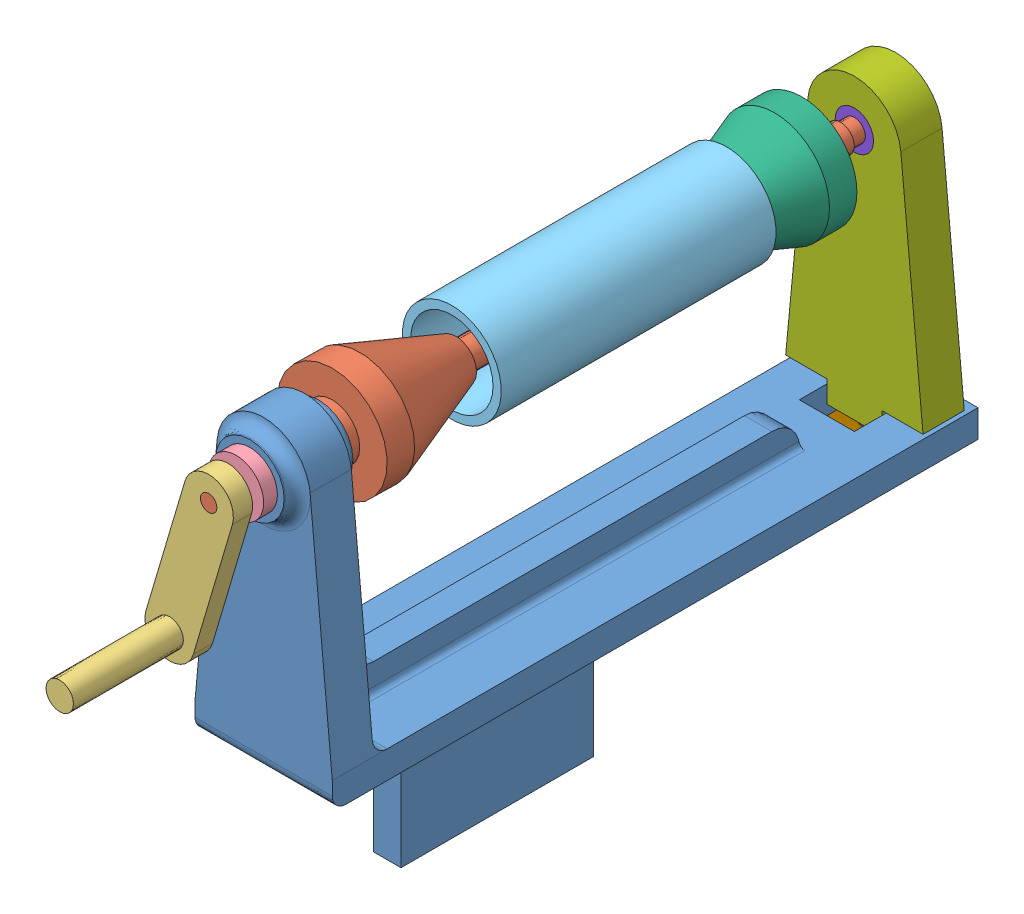
SolidWorks assembly Assem1, configuration Default. Lengths in mm.
Overall size (54.57 172.28 302.5).
10 component instances, 10 part files, 17 mates.
Components (placement in the parent):
- Ak Body-1: Ak Body [Default] at (61.2452 109.5735 296.2615) size (50 162 240)
- Ak Spindle-1: Ak Spindle [Default] at (61.2452 204.5735 73.7615) x (0 0 1) z (-0.495545 0.868582 0) size (250 40 40)
- Ak Spindle Handle-1: Ak Spindle Handle [Default] at (54.147 180.6024 323.7615) x (-0.958846 0.283926 0) z (0 0 -1) size (18 68 47)
- Ak Spindle Locking Nut-1: Ak Spindle Locking Nut [Default] at (61.2452 204.5735 308.7615) x (0.507715 0.861525 0) z (0 0 1) size (20 20 5)
- Ak Coil Former-1: Ak Coil Former [Default] at (61.2452 204.5735 235.2599) x (0 0 -1) z (0.4215 -0.906829 0) size (100 36 36)
- Ak Coil Former Locking Nut-1: Ak Coil Former Locking Nut [Default] at (61.2452 204.5735 107.8232) x (0 0 1) z (-0.998233 -0.059423 0) size (45 40 40)
- Ak End Bearing-1: Ak End Bearing [Default] at (61.2452 113.1815 81.2615) size (50 108.39 15)
- Ak Bush-1: Ak Bush [Default] at (61.2452 204.5735 88.7615) x (1 0 0) z (0 1 0) size (14 15 14)
- Ak Washer-1: Ak Washer [Default] at (61.2452 109.5735 81.2615) x (1 0 0) z (0 -1 0) size (40 40 5)
- Ak Bolt-1: Ak Bolt [Default] at (61.2452 104.5735 81.2615) x (0.833505 0 -0.552512) z (0.552512 0 0.833505) size (14 31.4 16.17)
Mates (geometry in assembly coordinates):
- Concentric1: concentric aligned: cylinder of Ak Body-1 through (61.2452 204.5735 283.7615) axis (0 0 -1) radius 5; cylinder of Ak Spindle-1 through (61.2452 204.5735 73.7615) axis (0 0 -1) radius 5
- Coincident1: coincident anti-aligned: plane of Ak Body-1 through (61.2452 204.5735 283.7615) normal (0 0 -1); plane of Ak Spindle-1 through (69.931 209.529 283.7615) normal (0 0 1)
- Concentric2: concentric aligned: cylinder of Ak Spindle-1 through (61.2452 204.5735 73.7615) axis (0 0 -1) radius 3; cylinder of Ak Spindle Handle-1 through (61.2452 204.5735 316.7615) axis (0 0 -1) radius 3
- Coincident2: coincident anti-aligned: plane of Ak Spindle-1 through (64.7195 206.5557 316.7615) normal (0 0 1); plane of Ak Spindle Handle-1 through (47.0489 156.6312 316.7615) normal (0 0 -1)
- Concentric3: concentric aligned: cylinder of Ak Spindle-1 through (61.2452 204.5735 73.7615) axis (0 0 -1) radius 4; cylinder of Ak Spindle Locking Nut-1 through (61.2452 204.5735 313.7615) axis (0 0 -1) radius 4
- Coincident3: coincident anti-aligned: plane of Ak Body-1 through (61.2452 204.5735 308.7615) normal (0 0 1); plane of Ak Spindle Locking Nut-1 through (61.2452 204.5735 308.7615) normal (0 0 -1)
- Concentric4: concentric anti-aligned: cylinder of Ak Spindle-1 through (61.2452 204.5735 73.7615) axis (0 0 -1) radius 5; cylinder of Ak Coil Former-1 through (61.2452 204.5735 235.2599) axis (0 0 1) radius 15
- Concentric5: concentric aligned: cylinder of Ak Spindle-1 through (61.2452 204.5735 73.7615) axis (0 0 -1) radius 5; cylinder of Ak Coil Former Locking Nut-1 through (61.2452 204.5735 107.8232) axis (0 0 -1) radius 5
- Concentric6: concentric aligned: cylinder of Ak Spindle-1 through (61.2452 204.5735 73.7615) axis (0 0 -1) radius 4; cylinder of Ak End Bearing-1 through (61.2452 204.5735 88.7615) axis (0 0 -1) radius 7
- Concentric7: concentric anti-aligned: cylinder of Ak End Bearing-1 through (61.2452 204.5735 88.7615) axis (0 0 -1) radius 7; cylinder of Ak Bush-1 through (61.2452 204.5735 73.7615) axis (0 0 1) radius 7
- Coincident4: coincident aligned: plane of Ak End Bearing-1 through (61.2452 204.5735 73.7615) normal (0 0 -1); plane of Ak Bush-1 through (61.2452 204.5735 73.7615) normal (0 0 -1)
- Coincident5: coincident anti-aligned: plane of Ak Body-1 through (51.2452 59.5725 68.7615) normal (1 0 0); plane of Ak End Bearing-1 through (51.2452 113.1815 88.7615) normal (-1 0 0)
- Concentric10: concentric aligned: cylinder of Ak End Bearing-1 through (61.2452 113.1815 81.2615) axis (0 -1 0) radius 4; cylinder of Ak Bolt-1 through (61.2452 104.5735 81.2615) axis (0 -1 0) radius 4
- Coincident7: coincident anti-aligned: plane of Ak Body-1 through (36.2452 109.5735 303.7615) normal (0 -1 0); plane of Ak Washer-1 through (61.2452 109.5735 81.2615) normal (0 1 0)
- Concentric11: concentric anti-aligned: cylinder of Ak End Bearing-1 through (61.2452 113.1815 81.2615) axis (0 -1 0) radius 4; cylinder of Ak Washer-1 through (61.2452 104.5735 81.2615) axis (0 1 0) radius 4.5
- Coincident8: coincident anti-aligned: plane of Ak Washer-1 through (61.2452 104.5735 81.2615) normal (0 -1 0); plane of Ak Bolt-1 through (61.2452 104.5735 81.2615) normal (0 1 0)
- Coincident9: coincident aligned: plane of Ak Spindle-1 through (61.2452 204.5735 73.7615) normal (0 0 -1); plane of Ak End Bearing-1 through (61.2452 204.5735 73.7615) normal (0 0 -1)
